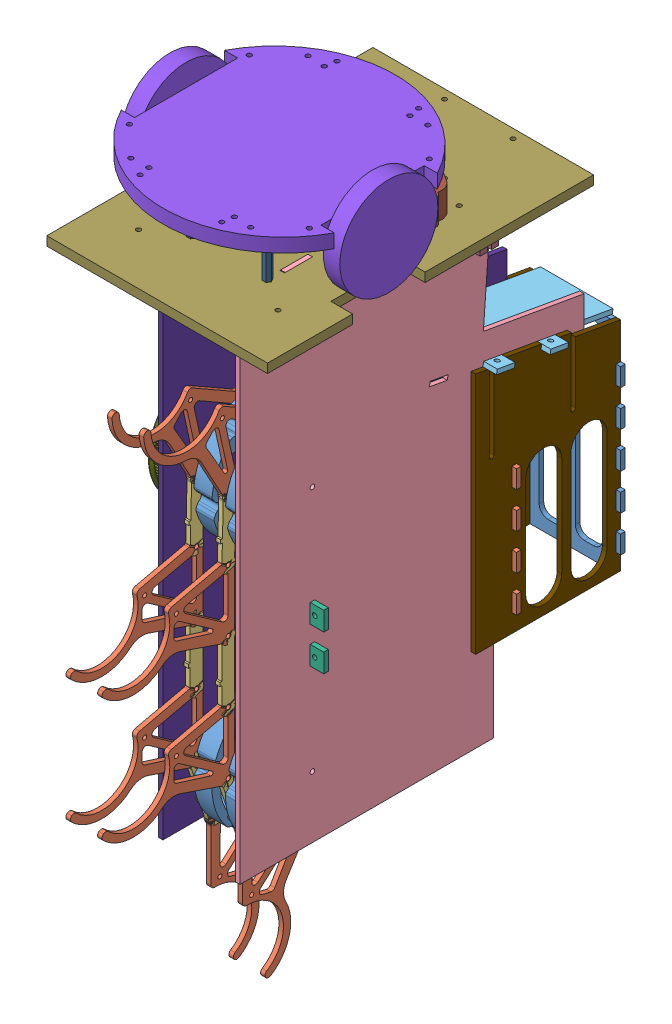
SolidWorks assembly FullAss, configuration Default. Lengths in mm.
Overall size (154.69 509.44 345.43).
64 component instances, 21 part files, 49 mates.
Components (placement in the parent):
- ChainAss-1: ChainAss [Default] at (-209.1402 -46.9879 -30.4465) size (15.88 406.12 263.22)
  - ChainPath-1: ChainPath [Default] at (256.5687 207.5359 404.6898)
  - TopGear-1: TopGear [Default] at (256.5687 380.2559 404.6898) x (0 -0.416633 -0.909075) z (0 -0.909075 0.416633) size (90.17 12.7 88.94)
  - TopGear-2: TopGear [Default] at (256.5687 207.5359 404.6898) x (0 -0.64296 -0.7659) z (0 -0.7659 0.64296) size (90.17 12.7 88.94)
  - BallHoldLink-1: BallHoldLink [Default] at (256.5687 197.6904 362.6472) x (0 0.999653 -0.026341) z (0 0.026341 0.999653) size (53.34 3.17 93.46)
  - InnerLink-1: InnerLink [Default] at (253.3937 240.8554 361.5098) x (0 1 0) z (0 0 -1) size (53.34 3.17 10.79)
  - InnerLink-2: InnerLink [Default] at (253.3937 166.2032 392.195) x (0 0.729208 -0.684292) z (0 -0.684292 -0.729208) size (53.34 3.17 10.79)
  - InnerLink-3: InnerLink [Default] at (253.3937 217.0203 447.8698) x (0 -0.948856 -0.315708) z (0 -0.315708 0.948856) size (53.34 3.17 10.79)
  - InnerLink-4: InnerLink [Default] at (253.3937 303.3803 447.8698) x (0 -1 0) z (0 0 1) size (53.34 3.17 10.79)
  - InnerLink-5: InnerLink [Default] at (253.3937 389.7275 446.8182) x (0 -0.999703 0.024354) z (0 0.024354 0.999703) size (53.34 3.17 10.79)
  - InnerLink-6: InnerLink [Default] at (253.3937 412.0043 375.423) x (0 0.219352 0.975646) z (0 0.975646 -0.219352) size (53.34 3.17 10.79)
  - InnerLink-7: InnerLink [Default] at (253.3937 327.9472 361.5098) x (0 1 0) z (0 0 -1) size (53.34 3.17 10.79)
  - BallHoldLink-2: BallHoldLink [Default] at (256.5687 176.0487 434.2375) x (0 -0.22801 -0.973659) z (0 0.973659 -0.22801) size (53.34 3.17 93.46)
  - BallHoldLink-3: BallHoldLink [Default] at (256.5687 260.2003 447.8698) x (0 -1 0) z (0 0 -1) size (53.34 3.17 93.46)
  - BallHoldLink-4: BallHoldLink [Default] at (256.5687 346.5603 447.8698) x (0 -1 0) z (0 0 -1) size (53.34 3.17 93.46)
  - BallHoldLink-5: BallHoldLink [Default] at (256.5687 421.4759 417.5514) x (0 -0.735258 0.677787) z (0 -0.677787 -0.735258) size (53.34 3.17 93.46)
  - BallHoldLink-6: BallHoldLink [Default] at (256.5687 371.1272 361.5098) x (0 0.946667 0.322213) z (0 -0.322213 0.946667) size (53.34 3.17 93.46)
  - BallHoldLink-7: BallHoldLink [Default] at (256.5687 284.7672 361.5098) x (0 1 0) z (0 0 1) size (53.34 3.17 93.46)
- SideFrameRight-1: SideFrameRight [Default] at (63.3035 466.6179 247.2433) x (0 0 -1) z (-1 0 0) size (241.3 355.6 3.17)
- ChainAss-2: ChainAss [Default] at (-231.3652 -46.9879 -30.4465) size (15.88 406.12 263.22)
  - ChainPath-1: ChainPath [Default] at (256.5687 207.5359 404.6898)
  - TopGear-1: TopGear [Default] at (256.5687 380.2559 404.6898) x (0 -0.416633 -0.909075) z (0 -0.909075 0.416633) size (90.17 12.7 88.94)
  - TopGear-2: TopGear [Default] at (256.5687 207.5359 404.6898) x (0 -0.64296 -0.7659) z (0 -0.7659 0.64296) size (90.17 12.7 88.94)
  - BallHoldLink-1: BallHoldLink [Default] at (256.5687 197.6904 362.6472) x (0 0.999653 -0.026341) z (0 0.026341 0.999653) size (53.34 3.17 93.46)
  - InnerLink-1: InnerLink [Default] at (253.3937 240.8554 361.5098) x (0 1 0) z (0 0 -1) size (53.34 3.17 10.79)
  - InnerLink-2: InnerLink [Default] at (253.3937 166.2032 392.195) x (0 0.729208 -0.684292) z (0 -0.684292 -0.729208) size (53.34 3.17 10.79)
  - InnerLink-3: InnerLink [Default] at (253.3937 217.0203 447.8698) x (0 -0.948856 -0.315708) z (0 -0.315708 0.948856) size (53.34 3.17 10.79)
  - InnerLink-4: InnerLink [Default] at (253.3937 303.3803 447.8698) x (0 -1 0) z (0 0 1) size (53.34 3.17 10.79)
  - InnerLink-5: InnerLink [Default] at (253.3937 389.7275 446.8182) x (0 -0.999703 0.024354) z (0 0.024354 0.999703) size (53.34 3.17 10.79)
  - InnerLink-6: InnerLink [Default] at (253.3937 412.0043 375.423) x (0 0.219352 0.975646) z (0 0.975646 -0.219352) size (53.34 3.17 10.79)
  - InnerLink-7: InnerLink [Default] at (253.3937 327.9472 361.5098) x (0 1 0) z (0 0 -1) size (53.34 3.17 10.79)
  - BallHoldLink-2: BallHoldLink [Default] at (256.5687 176.0487 434.2375) x (0 -0.22801 -0.973659) z (0 0.973659 -0.22801) size (53.34 3.17 93.46)
  - BallHoldLink-3: BallHoldLink [Default] at (256.5687 260.2003 447.8698) x (0 -1 0) z (0 0 -1) size (53.34 3.17 93.46)
  - BallHoldLink-4: BallHoldLink [Default] at (256.5687 346.5603 447.8698) x (0 -1 0) z (0 0 -1) size (53.34 3.17 93.46)
  - BallHoldLink-5: BallHoldLink [Default] at (256.5687 421.4759 417.5514) x (0 -0.735258 0.677787) z (0 -0.677787 -0.735258) size (53.34 3.17 93.46)
  - BallHoldLink-6: BallHoldLink [Default] at (256.5687 371.1272 361.5098) x (0 0.946667 0.322213) z (0 -0.322213 0.946667) size (53.34 3.17 93.46)
  - BallHoldLink-7: BallHoldLink [Default] at (256.5687 284.7672 361.5098) x (0 1 0) z (0 0 1) size (53.34 3.17 93.46)
- EndScoop-2: EndScoop [Default] at (9.3285 355.2065 304.7517) x (1 0 0) z (0 0.173648 0.984808) size (76.2 3.17 139.7)
- SpacePlate-1: SpacePlate [Default] at (9.3285 276.1179 375.8308) x (1 0 0) z (0 1 0) size (76.2 3.17 50.8)
- 90Support-1: 90Support [Default] at (6.1535 466.6179 298.0433) x (0 0 -1) z (1 0 0) size (13.26 25.4 25.4)
- 90Support-2: 90Support [Default] at (6.1535 466.6179 425.0433) x (0 0 -1) z (1 0 0) size (13.26 25.4 25.4)
- RSLKAss-1: RSLKAss [Default] at (8.7532 602.6902 504.5568) x (1 0 0) z (0 0 -1) size (154.69 120.83 228.6)
  - RSLKRobot-1: RSLKRobot [Default] at (-48.6373 76.7378 171.8377) size (153.54 68.83 162.51)
  - 1inHexSpacer-1: 1inHexSpacer [Default] at (-16.032 111.7898 197.7688) x (0.5 0 0.866025) z (0.866025 0 -0.5) size (5.57 31.75 4.83)
  - 1inHexSpacer-3: 1inHexSpacer [Default] at (67.9824 111.7898 197.7688) x (0.5 0 0.866025) z (0.866025 0 -0.5) size (5.57 31.75 4.83)
  - .75inHexSpacer-1: .75inHexSpacer [Default] at (52.5182 129.7222 100.832) x (1 0 0) z (0 0 -1) size (5.57 25.4 4.83)
  - .75inHexSpacer-2: .75inHexSpacer [Default] at (-0.5678 129.7222 191.0274) x (1 0 0) z (0 0 -1) size (5.57 25.4 4.83)
  - .75inHexSpacer-3: .75inHexSpacer [Default] at (52.5182 129.7222 191.0274) x (1 0 0) z (0 0 -1) size (5.57 25.4 4.83)
  - .75inHexSpacer-4: .75inHexSpacer [Default] at (-0.5678 129.7222 100.832) x (1 0 0) z (0 0 -1) size (5.57 25.4 4.83)
  - 1inHexSpacer-4: 1inHexSpacer [Default] at (-2.6646 111.7898 204.6548) x (0.5 0 0.866025) z (0.866025 0 -0.5) size (5.57 31.75 4.83)
  - 1inHexSpacer-5: 1inHexSpacer [Default] at (54.615 111.7898 204.6548) x (0.5 0 0.866025) z (0.866025 0 -0.5) size (5.57 31.75 4.83)
  - RSLKSpacePlate-1: RSLKSpacePlate [Default] at (67.9824 114.9648 197.7688) x (-1 0 0) z (0 0 -1) size (108.14 17.78 33.54)
  - RSLKBasePlate-2: RSLKBasePlate [Default] at (-0.5678 129.7222 191.276) size (154.69 6.35 228.6)
  - MotorMount-1: MotorMount [Default] at (-2.3457 156.0722 248.282) x (0 -1 0) z (1 0 0) size (46 58 63)
- Motor-2: Motor [Default] at (69.4076 446.6179 256.2748) x (0 0.997126 0.07576) z (-1 0 0) size (25 25 75.5)
- SmallBeltPulley-1: SmallBeltPulley [Default] at (-12.0273 446.6179 256.2748) x (0 -0.996961 0.077904) z (0 0.077904 0.996961) size (23.29 20.35 23.29)
- BigBeltPulley-1: BigBeltPulley [Default] at (-2.6965 333.2679 374.2433) x (0 0.54457 0.838716) z (0 -0.838716 0.54457) size (80.29 17.85 80.29)
- 90Support-3: 90Support [Default] at (63.3035 466.6179 412.3433) x (0 0 1) z (-1 0 0) size (13.26 25.4 25.4)
- 90Support-4: 90Support [Default] at (63.3035 466.6179 285.3433) x (0 0 1) z (-1 0 0) size (13.26 25.4 25.4)
- SideFrameLeft2-1: SideFrameLeft2 [Default] at (9.3285 466.6179 247.2433) x (0 0 -1) z (-1 0 0) size (241.3 349.25 3.17)
- BallStorageSide-1: BallStorageSide [Default] at (63.3035 329.9244 161.3698) x (0 0 1) z (0 1 0) size (101.6 3.17 170.31)
- BallStoreBackPlate-1: BallStoreBackPlate [Default] at (63.3035 329.9244 161.3698) x (-1 0 0) z (0 0 1) size (69.85 152.4 3.17)
- BallStorageSide-3: BallStorageSide [Default] at (2.9785 329.9244 161.3698) x (0 0 1) z (0 1 0) size (101.6 3.17 170.31)
- BallStoreFrontPlate-1: BallStoreFrontPlate [Default] at (6.1535 177.5244 237.5698) x (1 0 0) z (0 0 -1) size (69.85 117.47 3.17)
Mates (geometry in assembly coordinates):
- Distance2: distance = 9.525 mm anti-aligned: plane of ChainAss-2/TopGear-2 through (37.9035 160.5479 374.2433) normal (1 0 0); plane of ChainAss-1/TopGear-2 through (47.4285 160.5479 374.2433) normal (-1 0 0)
- Concentric1: concentric aligned: circle of ChainAss-1/TopGear-2; cylinder of ChainAss-2/TopGear-2 through (12.5035 160.5479 374.2433) axis (1 0 0) radius 1.5875
- Concentric2: concentric aligned: cylinder of ChainAss-1/TopGear-1 through (34.7285 333.2679 374.2433) axis (1 0 0) radius 1.5875; circle of ChainAss-2/TopGear-1
- Coincident14: coincident anti-aligned: plane of SideFrameRight-1 through (60.1285 466.6179 247.2433) normal (-1 0 0); plane of EndScoop-2 through (60.1285 358.3333 304.2004) normal (1 0 0)
- Concentric3: concentric anti-aligned: circle of SideFrame-1; circle of ChainAss-2/TopGear-1
- Distance3: distance = 12.7 mm anti-aligned: plane of SideFrameRight-1 through (60.1285 466.6179 247.2433) normal (-1 0 0); plane of ChainAss-1/BallHoldLink-8 through (47.4285 230.9577 348.126) normal (1 0 0)
- Concentric4: concentric anti-aligned: circle of SideFrame-1; circle of ChainAss-2/TopGear-2
- Coincident16: coincident anti-aligned: plane of SideFrameRight-1 through (63.3035 350.7958 279.7376) normal (0 0.984808 -0.173648); plane of EndScoop-2 through (9.3285 355.2065 304.7517) normal (0 -0.984808 0.173648)
- Coincident41: coincident anti-aligned: plane of SideFrameRight-1 through (60.1285 466.6179 247.2433) normal (0 1 0); plane of RSLKAss-1/RSLKBasePlate-1 through (8.1855 466.6179 313.2808) normal (0 -1 0)
- Coincident46: coincident aligned: plane of RSLKAss-1/MotorMount-1 through (69.4076 446.6179 256.2748) normal (1 0 0); plane of Motor-2 through (69.4076 446.6179 256.2748) normal (1 0 0)
- Concentric21: concentric anti-aligned: cylinder of RSLKAss-1/MotorMount-1 through (69.4076 446.6179 256.2748) axis (-1 0 0) radius 13.5; cylinder of Motor-2 through (6.4076 446.6179 256.2748) axis (1 0 0) radius 12.5
- Concentric22: concentric anti-aligned: cylinder of Motor-2 through (-6.0924 446.6179 256.2748) axis (1 0 0) radius 2; cylinder of SmallBeltPulley-1 through (5.3227 446.6179 256.2748) axis (-1 0 0) radius 2.0955
- Coincident48: coincident anti-aligned: plane of 90Support-2 through (6.1535 466.6179 412.3433) normal (0 1 0); plane of RSLKAss-1/RSLKBasePlate-1 through (8.1855 466.6179 313.2808) normal (0 -1 0)
- Coincident50: coincident anti-aligned: plane of 90Support-1 through (6.1535 466.6179 285.3433) normal (0 1 0); plane of RSLKAss-1/RSLKBasePlate-1 through (8.1855 466.6179 313.2808) normal (0 -1 0)
- Concentric26: concentric aligned: cylinder of SideFrameRight-1 through (55.6835 446.2979 418.6933) axis (1 0 0) radius 1.5875; cylinder of 90Support-3 through (47.4285 446.2979 418.6933) axis (1 0 0) radius 1.5875
- Coincident52: coincident anti-aligned: plane of SideFrameRight-1 through (63.3035 466.6179 247.2433) normal (1 0 0); plane of 90Support-3 through (63.3035 466.6179 425.0433) normal (-1 0 0)
- Coincident54: coincident anti-aligned: plane of RSLKAss-1/RSLKBasePlate-1 through (8.1855 466.6179 313.2808) normal (0 -1 0); plane of 90Support-3 through (63.3035 466.6179 425.0433) normal (0 1 0)
- Concentric27: concentric aligned: cylinder of SideFrameRight-1 through (55.6835 446.2979 291.6933) axis (1 0 0) radius 1.5875; cylinder of 90Support-4 through (47.4285 446.2979 291.6933) axis (1 0 0) radius 1.5875
- Coincident55: coincident anti-aligned: plane of SideFrameRight-1 through (63.3035 466.6179 247.2433) normal (1 0 0); plane of 90Support-4 through (63.3035 466.6179 298.0433) normal (-1 0 0)
- Coincident56: coincident anti-aligned: plane of RSLKAss-1/RSLKBasePlate-1 through (8.1855 466.6179 313.2808) normal (0 -1 0); plane of 90Support-4 through (63.3035 466.6179 298.0433) normal (0 1 0)
- Lock1: lock: unknown of RSLKAss-1/RSLKBasePlate-2; unknown of 90Support-4
- Coincident60: coincident anti-aligned: plane of SideFrameRight-1 through (70.2885 441.2179 372.6558) normal (0 0 1); plane of SpacePlate-1 through (9.3285 276.1179 372.6558) normal (0 0 -1)
- Coincident61: coincident anti-aligned: plane of SideFrameRight-1 through (70.2885 225.3179 247.2433) normal (0 1 0); plane of SpacePlate-1 through (9.3285 225.3179 372.6558) normal (0 -1 0)
- Coincident62: coincident anti-aligned: plane of SideFrameRight-1 through (60.1285 466.6179 247.2433) normal (-1 0 0); plane of SpacePlate-1 through (60.1285 276.1179 372.6558) normal (1 0 0)
- Concentric31: concentric aligned: cylinder of SideFrameRight-1 through (63.3035 160.5479 374.2433) axis (-1 0 0) radius 1.5875; cylinder of SideFrameLeft2-1 through (9.3285 160.5479 374.2433) axis (-1 0 0) radius 1.5875
- Concentric32: concentric aligned: cylinder of SideFrameRight-1 through (63.3035 333.2679 374.2433) axis (-1 0 0) radius 1.5875; cylinder of SideFrameLeft2-1 through (9.3285 333.2679 374.2433) axis (-1 0 0) radius 1.5875
- Distance7: distance = 50.8 mm anti-aligned: plane of SideFrameLeft2-1 through (9.3285 466.6179 247.2433) normal (1 0 0); plane of SideFrameRight-1 through (60.1285 466.6179 247.2433) normal (-1 0 0)
- Concentric33: concentric anti-aligned: cylinder of BigBeltPulley-1 through (-18.0465 333.2679 374.2433) axis (1 0 0) radius 7.5; cylinder of SideFrameLeft2-1 through (9.3285 333.2679 374.2433) axis (-1 0 0) radius 1.5875
- Distance8: distance = 6.35 mm anti-aligned: plane of SideFrameLeft2-1 through (6.1535 466.6179 247.2433) normal (-1 0 0); plane of BigBeltPulley-1 through (-0.1965 333.2679 374.2433) normal (1 0 0)
- Concentric34: concentric anti-aligned: cylinder of 90Support-2 through (22.0285 446.2979 418.6933) axis (-1 0 0) radius 1.5875; cylinder of SideFrameLeft2-1 through (1.7085 446.2979 418.6933) axis (1 0 0) radius 1.5875
- Coincident66: coincident anti-aligned: plane of 90Support-2 through (6.1535 466.6179 412.3433) normal (0 1 0); plane of RSLKAss-1/RSLKBasePlate-1 through (8.1855 466.6179 313.2808) normal (0 -1 0)
- Coincident67: coincident anti-aligned: plane of 90Support-2 through (6.1535 466.6179 412.3433) normal (1 0 0); plane of SideFrameLeft2-1 through (6.1535 466.6179 247.2433) normal (-1 0 0)
- Concentric35: concentric anti-aligned: cylinder of 90Support-1 through (22.0285 446.2979 291.6933) axis (-1 0 0) radius 1.5875; cylinder of SideFrameLeft2-1 through (1.7085 446.2979 291.6933) axis (1 0 0) radius 1.5875
- Coincident68: coincident anti-aligned: plane of 90Support-1 through (6.1535 466.6179 285.3433) normal (0 1 0); plane of RSLKAss-1/RSLKBasePlate-1 through (8.1855 466.6179 313.2808) normal (0 -1 0)
- Coincident69: coincident anti-aligned: plane of 90Support-1 through (6.1535 466.6179 285.3433) normal (1 0 0); plane of SideFrameLeft2-1 through (6.1535 466.6179 247.2433) normal (-1 0 0)
- Coincident70: coincident anti-aligned: plane of SideFrameRight-1 through (63.3035 346.3852 254.7235) normal (0 -0.173648 -0.984808); plane of EndScoop-2 through (60.1285 346.3852 254.7235) normal (0 0.173648 0.984808)
- Coincident71: coincident anti-aligned: plane of SideFrameRight-1 through (63.3035 466.6179 247.2433) normal (1 0 0); plane of BallStorageSide-1 through (63.3035 329.9244 161.3698) normal (-1 0 0)
- Coincident72: coincident anti-aligned: plane of EndScoop-2 through (9.3285 355.2065 304.7517) normal (0 -0.984808 0.173648); plane of BallStorageSide-1 through (66.4785 329.9244 161.3698) normal (0 0.984808 -0.173648)
- Distance9: distance = 12.7 mm anti-aligned: plane of ChainAss-1/InnerLink-6 through (47.4285 365.0164 344.9765) normal (1 0 0); plane of SideFrameRight-1 through (60.1285 466.6179 247.2433) normal (-1 0 0)
- Coincident74: coincident anti-aligned: plane of BallStorageSide-1 through (63.3035 329.9244 161.3698) normal (-1 0 0); plane of BallStoreBackPlate-1 through (63.3035 329.9244 164.5448) normal (1 0 0)
- Coincident75: coincident aligned: plane of BallStorageSide-1 through (66.4785 329.9244 161.3698) normal (0 0 -1); plane of BallStoreBackPlate-1 through (63.3035 329.9244 161.3698) normal (0 0 -1)
- Coincident76: coincident aligned: plane of BallStorageSide-1 through (66.4785 177.5244 161.3698) normal (0 -1 0); plane of BallStoreBackPlate-1 through (63.3035 177.5244 164.5448) normal (0 -1 0)
- Coincident78: coincident aligned: plane of BallStoreBackPlate-1 through (63.3035 329.9244 161.3698) normal (0 0 -1); plane of BallStorageSide-3 through (6.1535 329.9244 161.3698) normal (0 0 -1)
- Coincident79: coincident anti-aligned: plane of BallStoreBackPlate-1 through (6.1535 329.9244 164.5448) normal (-1 0 0); plane of BallStorageSide-3 through (6.1535 329.9244 161.3698) normal (1 0 0)
- Coincident80: coincident aligned: plane of BallStoreBackPlate-1 through (63.3035 177.5244 164.5448) normal (0 -1 0); plane of BallStorageSide-3 through (6.1535 177.5244 161.3698) normal (0 -1 0)
- Coincident84: coincident aligned: plane of BallStorageSide-3 through (6.1535 177.5244 161.3698) normal (0 -1 0); plane of BallStoreFrontPlate-1 through (6.1535 177.5244 234.3948) normal (0 -1 0)
- Coincident87: coincident anti-aligned: plane of BallStorageSide-3 through (2.9785 190.2244 234.3948) normal (0 0 1); plane of BallStoreFrontPlate-1 through (6.1535 177.5244 234.3948) normal (0 0 -1)
- Coincident88: coincident anti-aligned: plane of BallStorageSide-3 through (6.1535 329.9244 161.3698) normal (1 0 0); plane of BallStoreFrontPlate-1 through (6.1535 177.5244 234.3948) normal (-1 0 0)
- Coincident90: coincident anti-aligned: plane of SideFrameLeft2-1 through (9.3285 279.1244 310.7433) normal (0 -1 0); plane of BallStoreFrontPlate-1 through (6.1535 279.1244 234.3948) normal (0 1 0)
